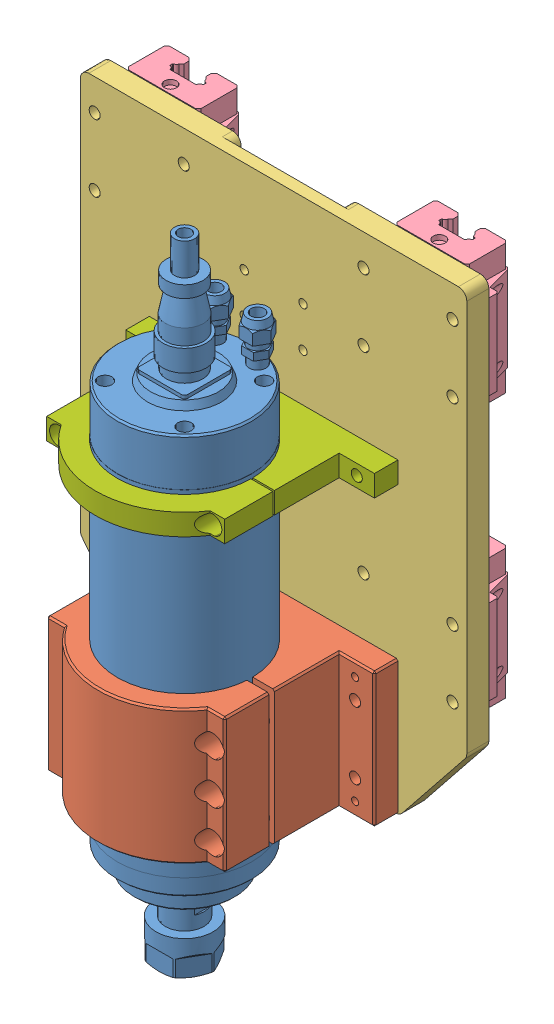
SolidWorks assembly Z axis, configuration Default. Lengths in mm.
Overall size (230 375.1 149.1).
13 component instances, 9 part files, 36 mates.
Components (placement in the parent):
- 2_2KW spindle-1: 2_2KW spindle [Default] at origin size (80 374.3 80)
- bracket-1: bracket [Default] at (0 -44.7 0) x (0 1 0) z (-1 0 0) size (80 104.4 148)
- tram plate-1: tram plate [Default] at (0 85.3 -54.1) x (-1 0 0) z (0 0 -1) size (230 290 13.1)
- HGW20CC-1: HGW20CC [Default] at (80 9.41 -82.1) x (0 1 0) z (1 0 0) size (77.26 24.9 63)
- HGW20CC-2: HGW20CC [Default] at (80 166.67 -82.1) x (0 1 0) z (1 0 0) size (77.26 24.9 63)
- HGW20CC-3: HGW20CC [Default] at (-80 9.41 -82.1) x (0 1 0) z (1 0 0) size (77.26 24.9 63)
- HGW20CC-4: HGW20CC [Default] at (-80 166.67 -82.1) x (0 -1 0) z (-1 0 0) size (77.26 24.9 63)
- SFU1204 nut housing-1: SFU1204 nut housing [Default] at (0 120.2 -81.1) x (1 0 0) z (0 1 0) size (50 30 36.1)
- nut_Z-1: nut_Z [z-axis] at (0 146.8 -81.1) x (0 0 1) z (0 1 0) size (29.8 42 35)
- bracket top-1: bracket top [Default] at (0 85.3 0) size (148 12.7 106)
- Z Homing Block top-1: Z Homing Block top [Both] at (-37.5 52.1578 -66.1) x (1 0 0) z (0 1 0) size (15 23.56 85)
- socket head cap screw_am-1: socket head cap screw_am [B18.3.1M - 5 x 0.8 x 25 Hex SHCS -- 25NHX] at (-37.5 67.8 -48) x (0 0 -1) z (0.972122 -0.234476 0) size (30 8.5 8.5)
- socket head cap screw_am-2: socket head cap screw_am [B18.3.1M - 5 x 0.8 x 25 Hex SHCS -- 25NHX] at (-37.5 7.8 -48) x (0 0 -1) z (1 0 0) size (30 8.5 8.5)
Mates (geometry in assembly coordinates):
- Coincident1: coordinate: point of 2_2KW spindle-1
- Concentric1: concentric anti-aligned: cylinder of 2_2KW spindle-1 through (0 128.3 0) axis (0 1 0) radius 40; cylinder of bracket-1 through (0 -4.7 0) axis (0 -1 0) radius 40
- Parallel1: parallel anti-aligned: plane of bracket-1 through (-74 -4.7 -53) normal (0 0 -1)
- Distance1: distance = 25 mm aligned: plane of bracket-1 through (0 -84.7 0) normal (0 -1 0); plane of 2_2KW spindle-1 through (0 -109.7 39.9) normal (0 -1 0)
- Coincident4: coincident anti-aligned: plane of bracket-1 through (-74 -4.7 -53) normal (0 0 -1); plane of tram plate-1 through (0 85.3 -53) normal (0 0 1)
- Width1: width anti-aligned: plane of bracket-1 through (-74 -4.7 -39) normal (-1 0 0); plane of bracket-1 through (74 -4.7 -39) normal (1 0 0); plane of tram plate-1 through (115 -34.7 -53) normal (1 0 0); plane of tram plate-1 through (-115 -34.7 -53) normal (-1 0 0)
- Coincident7: coincident anti-aligned: plane of tram plate-1 through (0 85.3 -66.1) normal (0 0 -1); plane of HGW20CC-2 through (111.5 245.453 -66.1) normal (0 0 1)
- Coincident8: coincident aligned: plane of tram plate-1 through (115 205.3 -53) normal (0 1 0); plane of HGW20CC-2 through (89.6464 205.3 -79.4386) normal (0 1 0)
- Coincident10: coincident anti-aligned: plane of tram plate-1 through (0 85.3 -66.1) normal (0 0 -1); plane of HGW20CC-1 through (48.5 88.193 -66.1) normal (0 0 1)
- Coincident12: coincident aligned: plane of HGW20CC-1 through (101.59 48.04 -89.53) normal (1 0 0); plane of HGW20CC-2 through (101.59 128.04 -89.53) normal (1 0 0)
- Coincident13: coincident anti-aligned: plane of tram plate-1 through (0 85.3 -66.1) normal (0 0 -1); plane of HGW20CC-4 through (-85.355 87.887 -66.1) normal (0 0 1)
- Coincident14: coincident aligned: plane of tram plate-1 through (115 205.3 -53) normal (0 1 0); plane of HGW20CC-4 through (-89.6464 205.3 -79.4386) normal (0 1 0)
- Coincident15: coincident anti-aligned: plane of tram plate-1 through (0 85.3 -66.1) normal (0 0 -1); plane of HGW20CC-3 through (-74.645 88.193 -66.1) normal (0 0 1)
- Coincident17: coincident aligned: plane of HGW20CC-3 through (-101.59 48.04 -89.53) normal (-1 0 0); plane of HGW20CC-4 through (-101.59 128.04 -89.53) normal (-1 0 0)
- Coincident18: coincident anti-aligned: plane of tram plate-1 through (0 85.3 -66.1) normal (0 0 -1); plane of SFU1204 nut housing-1 through (-25 156.3 -66.1) normal (0 0 1)
- Width2: width aligned: plane of SFU1204 nut housing-1 through (-25 156.3 -66.1) normal (-1 0 0); plane of tram plate-1 through (25 156.3 -96.1) normal (1 0 0); plane of SFU1204 nut housing-1 through (-115 -34.7 -53) normal (-1 0 0); plane of tram plate-1 through (115 -34.7 -53) normal (1 0 0)
- Concentric2: concentric anti-aligned: cylinder of SFU1204 nut housing-1 through (0 156.3 -81.1) axis (0 -1 0) radius 11; cylinder of nut_Z-1 through (0 173.8 -81.1) axis (0 1 0) radius 11
- Coincident19: coincident anti-aligned: plane of SFU1204 nut housing-1 through (0 156.3 -81.1) normal (0 1 0); plane of nut_Z-1 through (21 156.3 -81.1) normal (0 -1 0)
- Parallel2: parallel aligned: plane of tram plate-1 through (0 85.3 -66.1) normal (0 0 -1); plane of nut_Z-1 through (-21 156.3 -96) normal (0 0 -1)
- Distance4: distance = 6 mm aligned: plane of nut_Z-1 through (8 164.3 -81.1) normal (0 1 0); plane of tram plate-1 through (-32.5 170.3 -66.1) normal (0 1 0)
- Distance5: distance = 80 mm anti-aligned: plane of HGW20CC-2 through (89.6464 128.04 -79.4386) normal (0 -1 0); plane of HGW20CC-1 through (89.6464 48.04 -79.4386) normal (0 1 0)
- Coincident21: coincident aligned: plane of HGW20CC-1 through (89.6464 48.04 -79.4386) normal (0 1 0); plane of HGW20CC-3 through (-70.3536 48.04 -79.4386) normal (0 1 0)
- Coincident22: coincident aligned: plane of bracket-1 through (0 -84.7 0) normal (0 -1 0); plane of tram plate-1 through (75 -84.7 -53) normal (0 -1 0)
- Coincident23: coincident anti-aligned: plane of tram plate-1 through (0 85.3 -53) normal (0 0 1); plane of bracket top-1 through (-74 98 -53) normal (0 0 -1)
- Concentric4: concentric anti-aligned: cylinder of 2_2KW spindle-1 through (0 128.3 0) axis (0 1 0) radius 40; cylinder of bracket top-1 through (0 98 0) axis (0 -1 0) radius 40
- Distance6: distance = 90 mm anti-aligned: plane of bracket-1 through (0 -4.7 0) normal (0 1 0); plane of bracket top-1 through (0 85.3 0) normal (0 -1 0)
- Distance7: distance = 160 mm aligned: plane of HGW20CC-4 through (-86.5 128.04 -86.265) normal (1 0 0); plane of HGW20CC-2 through (73.5 205.3 -86.265) normal (1 0 0)
- Width3: width anti-aligned: plane of tram plate-1 through (-115 -34.7 -53) normal (-1 0 0); plane of HGW20CC-2 through (115 -34.7 -53) normal (1 0 0); plane of tram plate-1 through (111.5 245.453 -75.4558) normal (1 0 0); plane of HGW20CC-4 through (-111.5 87.887 -75.4558) normal (-1 0 0)
- Coincident24: coincident anti-aligned: plane of tram plate-1 through (0 85.3 -66.1) normal (0 0 -1); plane of Z Homing Block top-1 through (-34.325 22.1578 -66.1) normal (0 0 1)
- Parallel3: parallel aligned: plane of tram plate-1 through (-115 -34.7 -53) normal (-1 0 0); plane of Z Homing Block top-1 through (-45 9.6578 -71.6) normal (-1 0 0)
- Distance8: distance = 77.5 mm anti-aligned: plane of Z Homing Block-1 through (-37.5 52.1578 -66.1) normal (1 0 0); plane of tram plate-1 through (-115 -34.7 -53) normal (-1 0 0)
- Concentric6: concentric anti-aligned: cylinder of tram plate-1 through (-37.5 67.8 -46.1) axis (0 0 -1) radius 2.65; cylinder of socket head cap screw_am-1 through (-37.5 67.8 -16.25) axis (0 0 1) radius 4.25
- Coincident30: coincident anti-aligned: plane of tram plate-1 through (0 85.3 -53) normal (0 0 1); plane of socket head cap screw_am-1 through (-36.5035 71.9315 -53) normal (0 0 -1)
- Concentric7: concentric anti-aligned: cylinder of tram plate-1 through (-37.5 7.8 -46.1) axis (0 0 -1) radius 2.65; cylinder of socket head cap screw_am-2 through (-37.5 7.8 -16.25) axis (0 0 1) radius 4.25
- Coincident31: coincident anti-aligned: plane of tram plate-1 through (0 85.3 -53) normal (0 0 1); plane of socket head cap screw_am-2 through (-37.5 12.05 -53) normal (0 0 -1)
- Distance9: distance = 79.3578 mm aligned: plane of Z Homing Block top-1 through (-45 -5.3422 -50.3354) normal (0 -1 0); plane of tram plate-1 through (75 -84.7 -53) normal (0 -1 0)
